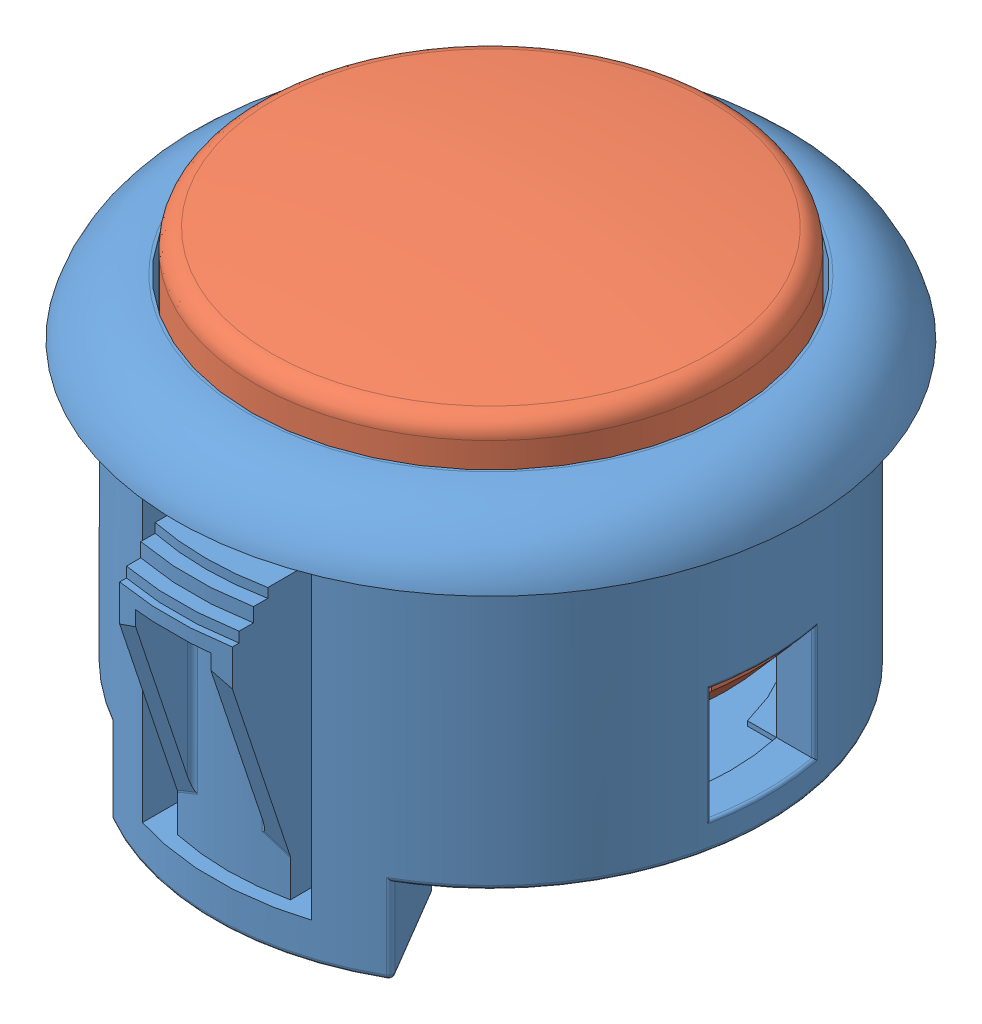
SolidWorks assembly Sanwa OBSF-30 assem, configuration Default. Lengths in mm.
Overall size (33.5 25.53 34.06).
2 component instances, 2 part files, 2 mates.
Components (placement in the parent):
- Sanwa OBSF-30 body-1: Sanwa OBSF-30 body [Default] at (-0.4248 -9.7351 -0.8051) size (33.5 22.5 34.06)
- Sanwa OBSF-30 plunger-1: Sanwa OBSF-30 plunger [Default] at (-0.4248 -0.206 -0.8051) size (28.05 16.02 25)
Mates (geometry in assembly coordinates):
- Concentric3: concentric anti-aligned: cylinder of Sanwa OBSF-30 body-1 through (-0.4248 -3.7351 -0.8051) axis (0 1 0) radius 12.75; cylinder of Sanwa OBSF-30 plunger-1 through (-0.4248 14.794 -0.8051) axis (0 -1 0) radius 12.5
- Coincident2: coincident anti-aligned: plane of Sanwa OBSF-30 body-1 through (19.5752 2.294 1.9449) normal (0 -1 0); plane of Sanwa OBSF-30 plunger-1 through (-0.4248 2.294 -0.8051) normal (0 1 0)
